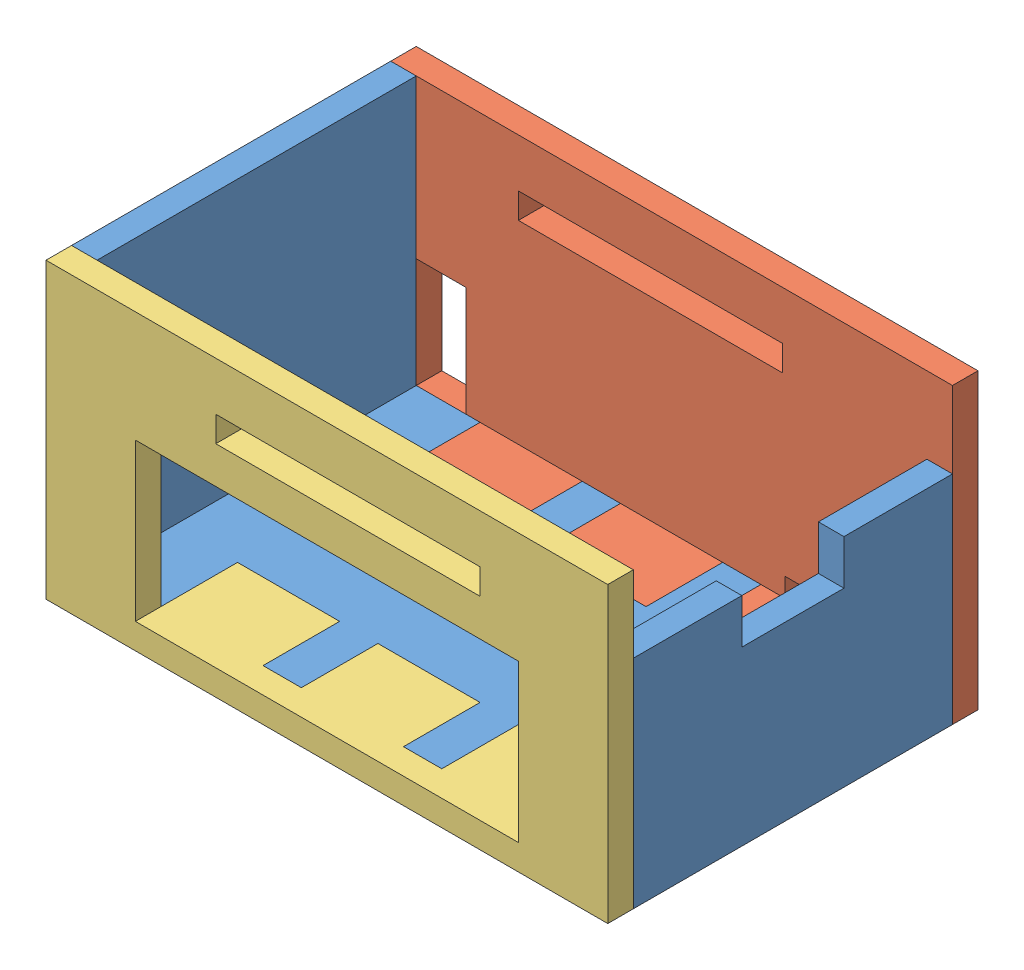
SolidWorks assembly assem_case_v1, configuration Default. Lengths in mm.
Overall size (44 23 29).
3 component instances, 3 part files, 7 mates.
Components (placement in the parent):
- case_v1_part1-1: case_v1_part1 [Default] at (22.3379 -8.2918 44.0733) size (44 23 25)
- case_v1_part3-1: case_v1_part3 [Default] at (22.3379 3.2082 29.5733) size (44 23 8)
- case_v1_part2-3: case_v1_part2 [Default] at (22.3379 3.2082 58.5733) x (-1 0 0) z (0 -1 0) size (44 8 23)
Mates (geometry in assembly coordinates):
- Coincident19: coincident anti-aligned: plane of case_v1_part2-3 through (29.3379 -8.2918 50.5733) normal (-1 0 0); plane of case_v1_part1-1 through (29.3379 -8.2918 56.5733) normal (1 0 0)
- Coincident20: coincident aligned: line of case_v1_part1-1 through (29.3379 -6.2918 50.5733) axis (1 0 0); line of case_v1_part2-3 through (29.3379 -6.2918 50.5733) axis (1 0 0)
- Coincident21: coincident anti-aligned: line of case_v1_part1-1 through (26.3379 -6.2918 56.5733) axis (1 0 0); line of case_v1_part2-3 through (29.3379 -6.2918 56.5733) axis (-1 0 0)
- Parallel8: parallel: plane of case_v1_part1-1 through (29.3379 -8.2918 37.5733) normal (0 0 -1); plane of case_v1_part3-1 through (23.7327 3.2082 37.5733) normal (0 0 1)
- Parallel9: parallel: plane of case_v1_part1-1 through (29.3379 -8.2918 31.5733) normal (1 0 0); plane of case_v1_part3-1 through (30.7327 -8.2918 37.5733) normal (-1 0 0)
- Coincident24: coincident: line of case_v1_part1-1 through (29.3379 -6.2918 37.5733) axis (1 0 0); line of case_v1_part3-1 through (38.7327 -6.2918 37.5733) axis (-1 0 0)
- Coincident26: coincident anti-aligned: line of case_v1_part1-1 through (29.3379 -6.2918 31.5733) axis (0 0 1); line of case_v1_part3-1 through (29.3379 -6.2918 37.5733) axis (0 0 -1)
